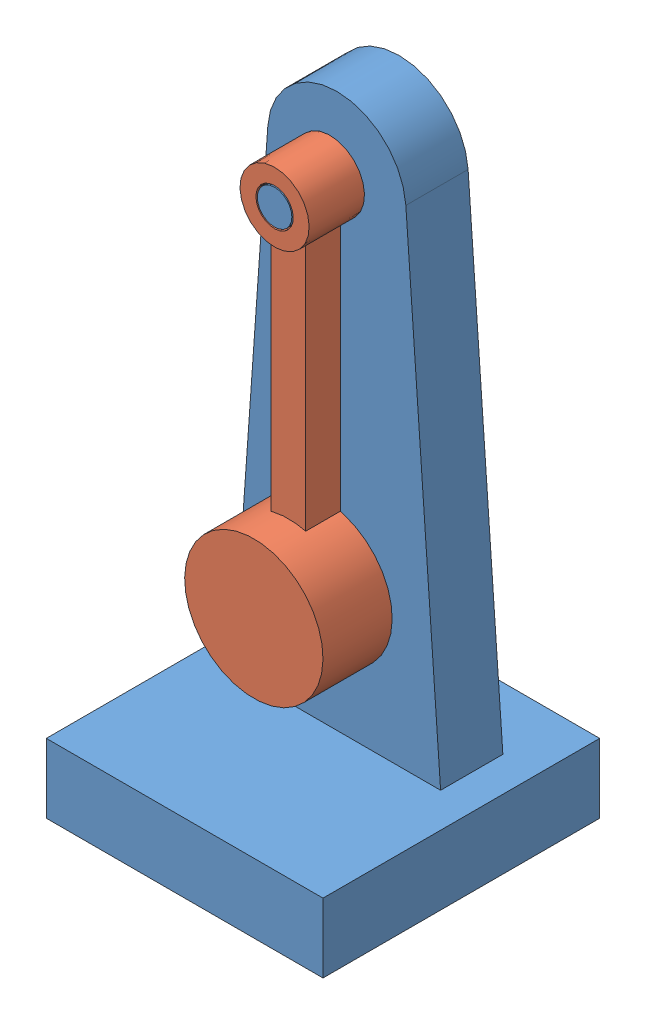
SolidWorks assembly Pendulum_assm, configuration Default. Lengths in mm.
Overall size (90.31 114.3 50.8).
3 component instances, 3 part files, 0 mates.
Components (placement in the parent):
- Pendulum_master_sketch-1: Pendulum_master_sketch [Default] at origin size (50.8 114.3 0) (hidden)
- Base-1: Base [Default] at origin size (50.8 114.3 50.8)
- Pendulum-1: Pendulum [Default] at (-69.5869 27.5715 5.08) x (0.728627 -0.68491 0) z (0 0 1) size (62.54 65.32 13.97)
